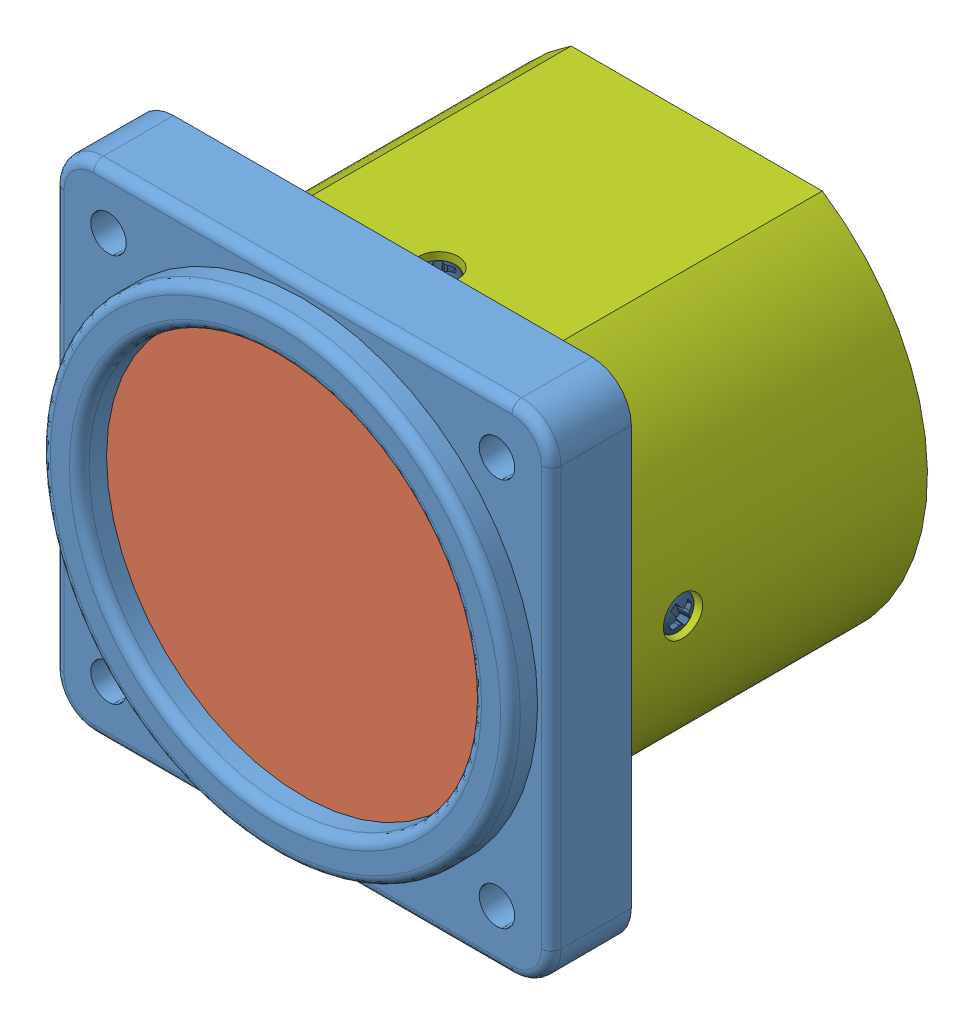
SolidWorks assembly Vertical Velocity Indicator, configuration Default. Lengths in mm.
Overall size (60.32 60.32 51.12).
23 component instances, 13 part files, 52 mates.
Components (placement in the parent):
- VVI Bezel-1: VVI Bezel [Default] at origin size (60.32 60.32 13.02)
- Airspeed Indicator Cover Glass-1: Airspeed Indicator Cover Glass [Default] at (0 0 9.7155) x (1 0 0) z (0 0 -1) size (49.91 49.91 1.59)
- Airspeed Indicator Dial Face Spacer-1: Airspeed Indicator Dial Face Spacer [Default] at (0 0 3.3655) size (49.91 49.91 4.76)
- VVI Dial Face-1: VVI Dial Face [Default] at (0 0 1.778) size (47.65 47.65 1.59)
- VVI Stepper Mount-1: VVI Stepper Mount [Default] at (0 0 1.778) x (0 -1 0) z (0 0 -1) size (44.93 49.4 18.35)
- Airspeed Indicator Pointer-1: Airspeed Indicator Pointer [Default] at (0 0 4.953) x (0.015812 0.999875 0) z (0 0 1) size (3.17 30.16 0.76)
- VVI Indicator Case-1: VVI Indicator Case [Connector Down] at (0 0 1.778) x (0 -1 0) z (0 0 -1) size (51.5 56.01 38.1)
- VID29-02-1: VID29-02 [Default] at (0 6 -12.223) x (1 0 0) z (0 -1 0) size (31.7 22.35 29.3)
- MD-40PL100-1: MD-40PL100 [Default] at (0 0 -34.925) x (0 0 -1) z (1 0 0) size (21.05 14 25)
- 90272A077_ZINC-PLTD STL PAN HEAD PHILLIPS MACHINE SCREW_2-56 X .250-1: 90272A077_ZINC-PLTD STL PAN HEAD PHILLIPS MACHINE SCREW_2-56 X .250 [90272A077] at (-10.0394 -17.3887 -8.4328) x (-0.440327 0.254223 0.861094) z (-0.5 -0.866025 0) size (4.24 4.24 7.94)
- 90272A077_ZINC-PLTD STL PAN HEAD PHILLIPS MACHINE SCREW_2-56 X .250-2: 90272A077_ZINC-PLTD STL PAN HEAD PHILLIPS MACHINE SCREW_2-56 X .250 [90272A077] at (0 15.5702 -6.762) x (0.738734 0 0.673998) z (0 1 0) size (4.24 4.24 7.94)
- 90272A077_ZINC-PLTD STL PAN HEAD PHILLIPS MACHINE SCREW_2-56 X .250-3: 90272A077_ZINC-PLTD STL PAN HEAD PHILLIPS MACHINE SCREW_2-56 X .250 [90272A077] at (20.0787 0 -8.4328) x (0 -0.815585 -0.578638) z (1 0 0) size (4.24 4.24 7.94)
- 93365A110_BRASS HEAT-SET INSERT FOR PLASTICS_2-56-1: 93365A110_BRASS HEAT-SET INSERT FOR PLASTICS_2-56 [Default] at (24.7015 0 -8.4328) x (0 0.381849 -0.924225) z (0 -0.924225 -0.381849) size (3.58 3.09 3.58)
- 93365A110_BRASS HEAT-SET INSERT FOR PLASTICS_2-56-4: 93365A110_BRASS HEAT-SET INSERT FOR PLASTICS_2-56 [Default] at (0 20.2286 -6.762) x (-0.98097 0 0.19416) z (-0.19416 0 -0.98097) size (3.58 3.09 3.58)
- 93365A110_BRASS HEAT-SET INSERT FOR PLASTICS_2-56-6: 93365A110_BRASS HEAT-SET INSERT FOR PLASTICS_2-56 [Default] at (-12.3508 -21.3921 -8.4328) x (0.792275 -0.45742 -0.403816) z (-0.349715 0.201908 -0.91484) size (3.58 3.09 3.58)
- 93365A102 - INSERT, 0-80, BRASS, FOR PLASTICS-1: 93365A102 - INSERT, 0-80, BRASS, FOR PLASTICS [Default] at (13.5 6 -5.523) x (0.015308 0.999883 0) z (-0.999883 0.015308 0) size (3.58 3.01 3.58)
- 93365A102 - INSERT, 0-80, BRASS, FOR PLASTICS-2: 93365A102 - INSERT, 0-80, BRASS, FOR PLASTICS [Default] at (-13.5 6 -5.523) x (0.015308 0.999883 0) z (-0.999883 0.015308 0) size (3.58 3.01 3.58)
- 91772A064 - PHS, 0-80 x .4375, 18-8-1: 91772A064 - PHS, 0-80 x .4375, 18-8 [91772A064] at (-13.5 6 -1.4105) x (0.653004 -0.757354 0) z (0 0 -1) size (2.95 2.95 12.24)
- 91772A064 - PHS, 0-80 x .4375, 18-8-2: 91772A064 - PHS, 0-80 x .4375, 18-8 [91772A064] at (13.5 6 -1.4105) x (0.764825 -0.644239 0) z (0 0 -1) size (2.95 2.95 12.24)
- 93365A102 - INSERT, 0-80, BRASS, FOR PLASTICS-3: 93365A102 - INSERT, 0-80, BRASS, FOR PLASTICS [Default] at (9.5 0 -34.925) x (0.982034 0.188703 0) z (0.188703 -0.982034 0) size (3.58 3.01 3.58)
- 93365A102 - INSERT, 0-80, BRASS, FOR PLASTICS-5: 93365A102 - INSERT, 0-80, BRASS, FOR PLASTICS [Default] at (-9.5 0 -34.925) x (0.934347 0.356365 0) z (0.356365 -0.934347 0) size (3.58 3.01 3.58)
- 91772A064 - PHS, 0-80 x .4375, 18-8-4: 91772A064 - PHS, 0-80 x .4375, 18-8 [91772A064] at (-9.5 0 -38.0375) x (-0.764825 -0.644239 0) z (0 0 1) size (2.95 2.95 12.24)
- 91772A064 - PHS, 0-80 x .4375, 18-8-6: 91772A064 - PHS, 0-80 x .4375, 18-8 [91772A064] at (9.5 0 -38.0375) x (-0.840631 -0.541608 0) z (0 0 1) size (2.95 2.95 12.24)
Mates (geometry in assembly coordinates):
- InPlace1: in place: plane of VVI Bezel-1 through (0 0 0) normal (0 0 1); moOrthogonalPlaneRef_w of VVI Bezel-1 through (0 0 0) normal (0 1 0); plane of VVI Bezel-1 through (0 0 0) normal (1 0 0); unknown of VVI Bezel-1
- Coincident1: coincident: plane of VVI Bezel-1; plane of assembly
- Coincident2: coincident: plane of VVI Bezel-1 through (0 0 0) normal (0 1 0); moOrthogonalPlaneRef_w of assembly
- Coincident3: coincident: plane of VVI Bezel-1 through (0 0 0) normal (1 0 0); moOrthogonalPlaneRef_w of assembly
- Concentric1: concentric: cylinder of VVI Bezel-1 through (0 0 81.3779) axis (0 0 -1) radius 25.3365; cylinder of Airspeed Indicator Cover Glass-1 through (0 0 8.128) axis (0 0 1) radius 24.9555
- Concentric2: concentric: cylinder of VVI Bezel-1 through (0 0 81.3779) axis (0 0 -1) radius 25.3365; cylinder of Airspeed Indicator Dial Face Spacer-1 through (0 0 8.128) axis (0 0 -1) radius 24.9555
- Concentric5: concentric: cylinder of VVI Bezel-1 through (0 0 81.3779) axis (0 0 -1) radius 25.3365; cylinder of VVI Dial Face-1 through (0 0 3.3655) axis (0 0 -1) radius 23.8252
- Parallel1: parallel: plane of VVI Bezel-1 through (30.1625 0 9.7155) normal (1 0 0); plane of VVI Dial Face-1 through (0 0 1.778) normal (1 0 0)
- Concentric9: concentric: cylinder of VVI Bezel-1 through (0 0 81.3779) axis (0 0 -1) radius 25.3365; cylinder of VVI Stepper Mount-1 through (0 0 -70.6505) axis (0 0 1) radius 24.7015
- Coincident7: coincident: plane of VVI Dial Face-1 through (0 0 1.778) normal (0 0 -1); plane of VVI Stepper Mount-1 through (0 0 1.778) normal (0 0 1)
- Distance1: distance = 1.5875 mm: plane of Airspeed Indicator Pointer-1 through (0 0 4.953) normal (0 0 -1); plane of VVI Dial Face-1 through (0 0 3.3655) normal (0 0 1)
- Coincident13: coincident: plane of Airspeed Indicator Dial Face Spacer-1 through (0 0 3.3655) normal (0 0 -1); plane of VVI Dial Face-1 through (0 0 3.3655) normal (0 0 1)
- Coincident58: coincident: plane of Airspeed Indicator Cover Glass-1 through (0 0 8.128) normal (0 0 -1); plane of Airspeed Indicator Dial Face Spacer-1 through (0 0 8.128) normal (0 0 1)
- Coincident59: coincident: plane of VVI Bezel-1 through (0 0 9.7155) normal (0 0 -1); plane of Airspeed Indicator Cover Glass-1 through (0 0 9.7155) normal (0 0 1)
- Parallel21: parallel: plane of assembly through (0 0 0) normal (0 1 0); plane of VVI Stepper Mount-1 through (0 0 1.778) normal (0 -1 0)
- Concentric50: concentric: cone of VVI Stepper Mount-1 through (24.7015 0 -8.4328) axis (-1 0 0); cone of 93365A110_BRASS HEAT-SET INSERT FOR PLASTICS_2-56-1 through (23.5915 0 -8.4328) axis (-1 0 0)
- Coincident62: coincident: plane of VVI Stepper Mount-1 through (24.7015 0 -8.4328) normal (1 0 0); plane of 93365A110_BRASS HEAT-SET INSERT FOR PLASTICS_2-56-1 through (24.7015 -0.6838 -6.7778) normal (1 0 0)
- Concentric51: concentric: cone of VVI Stepper Mount-1 through (0 20.2286 -6.762) axis (0 -1 0); cone of 93365A110_BRASS HEAT-SET INSERT FOR PLASTICS_2-56-4 through (0 19.1186 -6.762) axis (0 -1 0)
- Concentric53: concentric: cone of VVI Stepper Mount-1 through (-12.3508 -21.3921 -8.4328) axis (0.5 0.866025 0); cone of 93365A110_BRASS HEAT-SET INSERT FOR PLASTICS_2-56-6 through (-11.7958 -20.4309 -8.4328) axis (0.5 0.866025 0)
- Coincident67: coincident: plane of VVI Stepper Mount-1 through (-12.3508 -21.3921 -8.4328) normal (-0.5 -0.866025 0); plane of 93365A110_BRASS HEAT-SET INSERT FOR PLASTICS_2-56-6 through (-13.7695 -20.573 -7.7097) normal (-0.5 -0.866025 0)
- Concentric56: concentric: cylinder of VVI Stepper Mount-1 through (0 0 -70.6505) axis (0 0 1) radius 24.7015; cylinder of VVI Indicator Case-1 through (0 0 -38.1) axis (0 0 1) radius 25.3365
- Concentric57: concentric: circle of 93365A110_BRASS HEAT-SET INSERT FOR PLASTICS_2-56-1; cylinder of VVI Indicator Case-1 through (28.0035 0 -8.4328) axis (1 0 0) radius 2.3813
- Concentric58: concentric: cylinder of 90272A077_ZINC-PLTD STL PAN HEAD PHILLIPS MACHINE SCREW_2-56 X .250-3 through (20.0787 0 -8.4328) axis (-1 0 0) radius 2.1209; circle of 93365A110_BRASS HEAT-SET INSERT FOR PLASTICS_2-56-1
- Concentric59: concentric: cylinder of 90272A077_ZINC-PLTD STL PAN HEAD PHILLIPS MACHINE SCREW_2-56 X .250-2 through (0 15.5702 -6.762) axis (0 -1 0) radius 2.1209; cylinder of VVI Indicator Case-1 through (0 23.495 -6.762) axis (0 1 0) radius 2.3813
- Concentric61: concentric: cylinder of VVI Dial Face-1 through (0 0 1.778) axis (0 0 1) radius 0.7937; cylinder of Airspeed Indicator Pointer-1 through (0 0 5.715) axis (0 0 -1) radius 0.5
- Concentric62: concentric: cone of VVI Stepper Mount-1 through (13.5 6 -5.523) axis (0 0 1); cone of 93365A102 - INSERT, 0-80, BRASS, FOR PLASTICS-1 through (13.5 6 -4.413) axis (0 0 1)
- Coincident68: coincident: plane of VVI Stepper Mount-1 through (13.5 6 -5.523) normal (0 0 -1); plane of 93365A102 - INSERT, 0-80, BRASS, FOR PLASTICS-1 through (13.4726 4.2095 -5.523) normal (0 0 -1)
- Concentric63: concentric: cone of VVI Stepper Mount-1 through (-13.5 6 -5.523) axis (0 0 1); cone of 93365A102 - INSERT, 0-80, BRASS, FOR PLASTICS-2 through (-13.5 6 -4.413) axis (0 0 1)
- Coincident69: coincident: plane of VVI Stepper Mount-1 through (-13.5 6 -5.523) normal (0 0 -1); plane of 93365A102 - INSERT, 0-80, BRASS, FOR PLASTICS-2 through (-13.5274 4.2095 -5.523) normal (0 0 -1)
- Concentric64: concentric: cylinder of VVI Dial Face-1 through (0 0 1.778) axis (0 0 1) radius 0.7937; cylinder of VID29-02-1 through (0 0 -5.823) axis (0 0 -1) radius 0.5
- Concentric65: concentric: circle of VVI Stepper Mount-1; cylinder of VID29-02-1 through (13.5 6 -12.523) axis (0 0 -1) radius 0.925
- Coincident70: coincident: plane of VVI Stepper Mount-1 through (13.5 6 -5.523) normal (0 0 -1); plane of VID29-02-1 through (13.5 6 -5.523) normal (0 0 1)
- Concentric66: concentric: cylinder of VID29-02-1 through (-13.5 6 -12.523) axis (0 0 -1) radius 0.925; cylinder of 91772A064 - PHS, 0-80 x .4375, 18-8-1 through (-13.5 6 -1.4105) axis (0 0 1) radius 1.4732
- Coincident71: coincident: plane of VID29-02-1 through (0 6 -12.523) normal (0 0 -1); plane of 91772A064 - PHS, 0-80 x .4375, 18-8-1 through (-13.5 6 -12.523) normal (0 0 1)
- Concentric67: concentric: cylinder of VID29-02-1 through (13.5 6 -12.523) axis (0 0 -1) radius 0.925; cylinder of 91772A064 - PHS, 0-80 x .4375, 18-8-2 through (13.5 6 -1.4105) axis (0 0 1) radius 1.4732
- Coincident72: coincident: plane of VID29-02-1 through (0 6 -12.523) normal (0 0 -1); plane of 91772A064 - PHS, 0-80 x .4375, 18-8-2 through (13.5 6 -12.523) normal (0 0 1)
- Concentric68: concentric: cone of VVI Indicator Case-1 through (9.5 0 -34.925) axis (0 0 -1); cone of 93365A102 - INSERT, 0-80, BRASS, FOR PLASTICS-3 through (9.5 0 -36.035) axis (0 0 -1)
- Coincident73: coincident: plane of VVI Indicator Case-1 through (0 0 -34.925) normal (0 0 1); plane of 93365A102 - INSERT, 0-80, BRASS, FOR PLASTICS-3 through (7.7415 -0.3379 -34.925) normal (0 0 1)
- Concentric69: concentric: cone of VVI Indicator Case-1 through (-9.5 0 -34.925) axis (0 0 -1); cone of 93365A102 - INSERT, 0-80, BRASS, FOR PLASTICS-5 through (-9.5 0 -36.035) axis (0 0 -1)
- Coincident74: coincident: plane of VVI Indicator Case-1 through (0 0 -34.925) normal (0 0 1); plane of 93365A102 - INSERT, 0-80, BRASS, FOR PLASTICS-5 through (-11.1731 -0.6381 -34.925) normal (0 0 1)
- Concentric70: concentric: cylinder of VVI Indicator Case-1 through (0 0 1.779) axis (0 0 -1) radius 7.27; cylinder of MD-40PL100-1 through (0 0 -21.725) axis (0 0 -1) radius 6
- Coincident75: coincident: plane of VVI Indicator Case-1 through (0 0 -34.925) normal (0 0 1); plane of MD-40PL100-1 through (0 0 -34.925) normal (0 0 -1)
- Concentric71: concentric: cylinder of MD-40PL100-1 through (-9.5 0 -21.6477) axis (0 0 -1) radius 1.05; cylinder of 91772A064 - PHS, 0-80 x .4375, 18-8-4 through (-9.5 0 -38.0375) axis (0 0 -1) radius 1.4732
- Coincident76: coincident: plane of MD-40PL100-1 through (-9.5 0 -26.925) normal (0 0 1); plane of 91772A064 - PHS, 0-80 x .4375, 18-8-4 through (-9.5 0 -26.925) normal (0 0 -1)
- Concentric72: concentric: cylinder of MD-40PL100-1 through (9.5 0 -21.6477) axis (0 0 -1) radius 1.05; cylinder of 91772A064 - PHS, 0-80 x .4375, 18-8-6 through (9.5 0 -38.0375) axis (0 0 -1) radius 1.4732
- Coincident77: coincident: plane of MD-40PL100-1 through (9.5 0 -26.925) normal (0 0 1); plane of 91772A064 - PHS, 0-80 x .4375, 18-8-6 through (9.5 0 -26.925) normal (0 0 -1)
- Parallel22: parallel: plane of VVI Bezel-1 through (0 30.1625 9.7155) normal (0 1 0); plane of MD-40PL100-1 through (0 3.1 -34.925) normal (0 1 0)
- Coincident78: coincident: plane of VVI Stepper Mount-1 through (14.1764 20.2286 -70.6505) normal (0 1 0); plane of 93365A110_BRASS HEAT-SET INSERT FOR PLASTICS_2-56-4 through (1.7566 20.2286 -7.1097) normal (0 1 0)
- Coincident79: coincident: plane of VVI Indicator Case-1 through (-1.3526 21.9202 -6.762) normal (0 1 0); plane of 90272A077_ZINC-PLTD STL PAN HEAD PHILLIPS MACHINE SCREW_2-56 X .250-2 through (0 21.9202 -6.762) normal (0 -1 0)
- Concentric73: concentric: cylinder of VVI Indicator Case-1 through (-14.0017 -24.2517 -8.4328) axis (-0.5 -0.866025 0) radius 2.3813; cylinder of 90272A077_ZINC-PLTD STL PAN HEAD PHILLIPS MACHINE SCREW_2-56 X .250-1 through (-10.0394 -17.3887 -8.4328) axis (0.5 0.866025 0) radius 2.1209
- Coincident80: coincident: plane of VVI Indicator Case-1 through (-13.2143 -22.8879 -9.7853) normal (-0.5 -0.866025 0); plane of 90272A077_ZINC-PLTD STL PAN HEAD PHILLIPS MACHINE SCREW_2-56 X .250-1 through (-13.2143 -22.8879 -8.4328) normal (0.5 0.866025 0)
- Coincident81: coincident: plane of VVI Indicator Case-1 through (26.4287 -1.3526 -8.4328) normal (1 0 0); plane of 90272A077_ZINC-PLTD STL PAN HEAD PHILLIPS MACHINE SCREW_2-56 X .250-3 through (26.4287 0 -8.4328) normal (-1 0 0)
